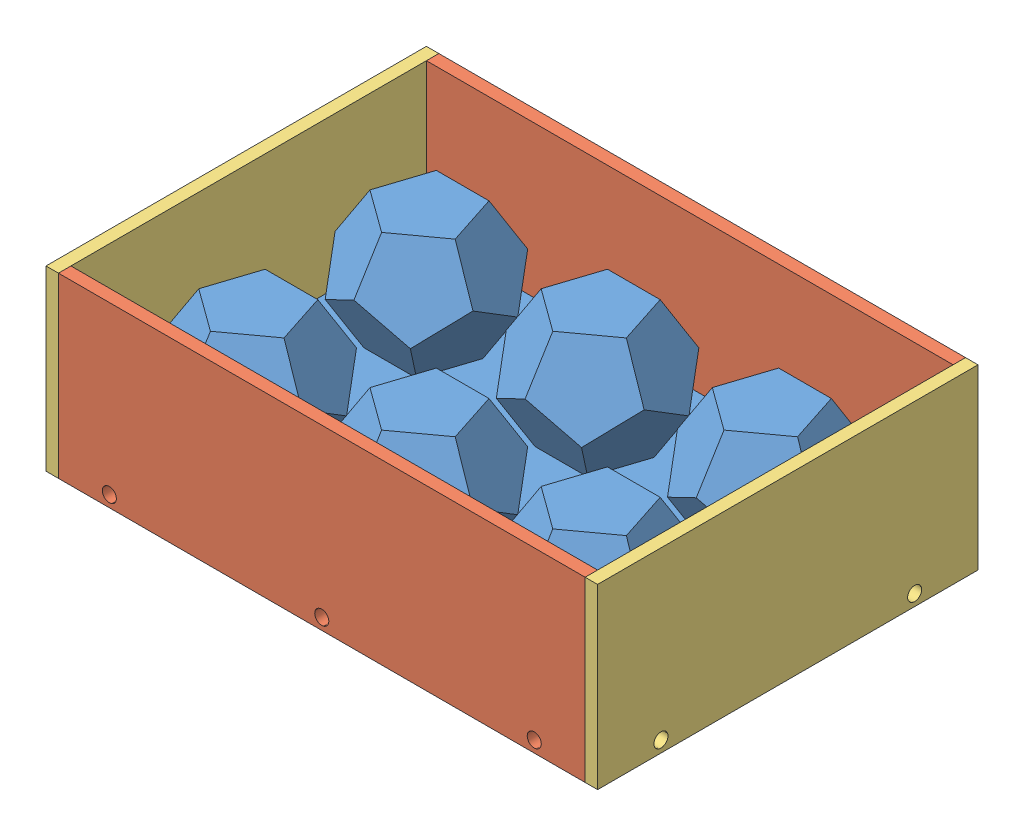
SolidWorks assembly 6 Part Mold, configuration Default. Lengths in mm.
Overall size (133 42.86 91.72).
5 component instances, 3 part files, 0 mates.
Components (placement in the parent):
- 6  Section Mold-1: 6  Section Mold [Default] at origin size (130 34.63 85.72)
- 3 Wall^6 Part Mold-1: 3 Wall^6 Part Mold [Default] at origin size (127 42.86 3) (virtual)
- 3 Wall^6 Part Mold-2: 3 Wall^6 Part Mold [Default] at (0 0 -88.725) size (127 42.86 3) (virtual)
- 2 Wall^6 Part Mold-1: 2 Wall^6 Part Mold [Default] at origin size (3 42.86 91.72) (virtual)
- 2 Wall^6 Part Mold-2: 2 Wall^6 Part Mold [Default] at (82.55 0 41.275) x (-1 0 0) z (0 0 -1) size (3 42.86 91.72) (virtual)
